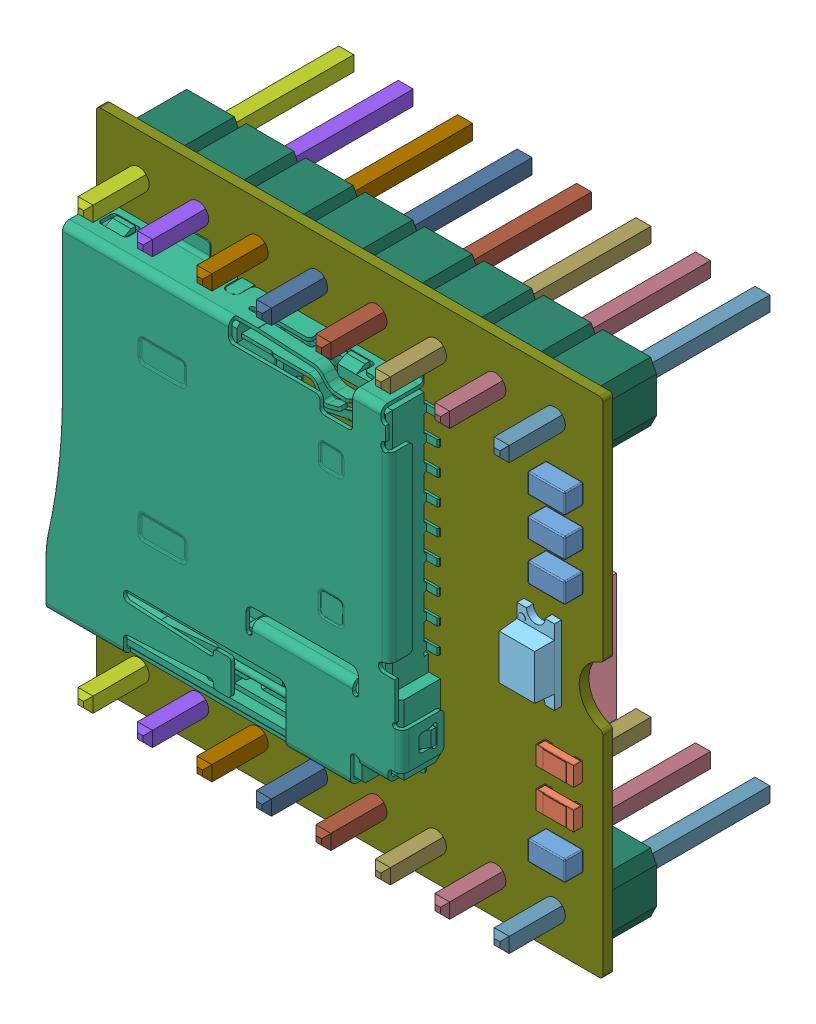
SolidWorks assembly MP3-TF-16P, configuration Default. Lengths in mm.
Overall size (21.94 21.51 11.54).
80 component instances, 16 part files, 0 mates.
Components (placement in the parent):
- Designator45-1: Designator45 [Default] at origin size (1.6 0.86 0.8)
  - User_Library-Chip_Capacitor2CAPC0603X33N-1: User_Library-Chip_Capacitor2CAPC0603X33N [Default] at (15.7476 3.0705 -0.7915) x (-1 0 0) z (0 0 -1) size (1.6 0.86 0.8)
- Designator44-1: Designator44 [Default] at origin size (1.6 0.86 0.8)
  - User_Library-Chip_Capacitor2CAPC0603X33N-1: User_Library-Chip_Capacitor2CAPC0603X33N [Default] at (19.202 3.0705 -0.7915) x (-1 0 0) z (0 0 -1) size (1.6 0.86 0.8)
- Designator43-1: Designator43 [Default] at origin size (1.6 0.86 0.8)
  - User_Library-Chip_Capacitor2CAPC0603X33N-1: User_Library-Chip_Capacitor2CAPC0603X33N [Default] at (9.042 6.7293 -0.7915) x (-1 0 0) z (0 0 -1) size (1.6 0.86 0.8)
- Designator42-1: Designator42 [Default] at origin size (1.6 0.86 0.8)
  - User_Library-Chip_Capacitor2CAPC0603X33N-1: User_Library-Chip_Capacitor2CAPC0603X33N [Default] at (9.042 8.4227 -0.7915) x (-1 0 0) z (0 0 -1) size (1.6 0.86 0.8)
- Designator41-1: Designator41 [Default] at origin size (1.6 0.86 0.8)
  - User_Library-Chip_Capacitor2CAPC0603X33N-1: User_Library-Chip_Capacitor2CAPC0603X33N [Default] at (9.042 13.5027 -0.7915) x (-1 0 0) z (0 0 -1) size (1.6 0.86 0.8)
- Designator40-1: Designator40 [Default] at origin size (1.6 0.86 0.8)
  - User_Library-Chip_Capacitor2CAPC0603X33N-1: User_Library-Chip_Capacitor2CAPC0603X33N [Default] at (3.073 16.974 -0.7915) x (-1 0 0) z (0 0 -1) size (1.6 0.86 0.8)
- Designator39-1: Designator39 [Default] at origin size (1.6 0.86 0.8)
  - User_Library-Chip_Capacitor2CAPC0603X33N-1: User_Library-Chip_Capacitor2CAPC0603X33N [Default] at (9.4738 16.974 -0.7915) x (-1 0 0) z (0 0 -1) size (1.6 0.86 0.8)
- Designator38-1: Designator38 [Default] at origin size (1.6 0.86 0.8)
  - User_Library-Chip_Capacitor2CAPC0603X33N-1: User_Library-Chip_Capacitor2CAPC0603X33N [Default] at (12.6742 16.974 -0.7915) x (-1 0 0) z (0 0 -1) size (1.6 0.86 0.8)
- Designator37-1: Designator37 [Default] at origin size (1.6 0.86 0.8)
  - User_Library-Chip_Capacitor2CAPC0603X33N-1: User_Library-Chip_Capacitor2CAPC0603X33N [Default] at (19.075 16.974 -0.7915) x (-1 0 0) z (0 0 -1) size (1.6 0.86 0.8)
- Designator27-1: Designator27 [Default] at origin size (1.6 0.8 0.4)
  - User_Library-res0603-1-1: User_Library-res0603-1 [Default] at (12.2682 3.4955 -0.4115) x (1 0 0) z (0 0 -1) size (1.6 0.8 0.4)
- Designator26-1: Designator26 [Default] at origin size (1.6 0.8 0.4)
  - User_Library-res0603-1-1: User_Library-res0603-1 [Default] at (8.8138 3.4955 -0.4115) x (1 0 0) z (0 0 -1) size (1.6 0.8 0.4)
- Designator25-1: Designator25 [Default] at origin size (1.6 0.8 0.4)
  - User_Library-res0603-1-1: User_Library-res0603-1 [Default] at (5.3594 3.4955 -0.4115) x (1 0 0) z (0 0 -1) size (1.6 0.8 0.4)
- Designator24-1: Designator24 [Default] at origin size (1.6 0.8 0.4)
  - User_Library-res0603-1-1: User_Library-res0603-1 [Default] at (1.905 3.4955 -0.4115) x (1 0 0) z (0 0 -1) size (1.6 0.8 0.4)
- Designator23-1: Designator23 [Default] at origin size (1.6 0.8 0.4)
  - User_Library-res0603-1-1: User_Library-res0603-1 [Default] at (9.017 5.461 -0.4115) x (1 0 0) z (0 0 -1) size (1.6 0.8 0.4)
- Designator22-1: Designator22 [Default] at origin size (1.6 0.8 0.4)
  - User_Library-res0603-1-1: User_Library-res0603-1 [Default] at (9.017 10.541 -0.4115) x (1 0 0) z (0 0 -1) size (1.6 0.8 0.4)
- Designator21-1: Designator21 [Default] at origin size (1.6 0.8 0.4)
  - User_Library-res0603-1-1: User_Library-res0603-1 [Default] at (9.017 12.2343 -0.4115) x (1 0 0) z (0 0 -1) size (1.6 0.8 0.4)
- Designator20-1: Designator20 [Default] at origin size (1.6 0.8 0.4)
  - User_Library-res0603-1-1: User_Library-res0603-1 [Default] at (9.017 15.621 -0.4115) x (1 0 0) z (0 0 -1) size (1.6 0.8 0.4)
- Designator19-1: Designator19 [Default] at origin size (1.6 0.8 0.4)
  - User_Library-res0603-1-1: User_Library-res0603-1 [Default] at (6.2484 17.399 -0.4115) x (1 0 0) z (0 0 -1) size (1.6 0.8 0.4)
- Designator18-1: Designator18 [Default] at origin size (1.6 0.8 0.4)
  - User_Library-res0603-1-1: User_Library-res0603-1 [Default] at (15.8496 17.399 -0.4115) x (1 0 0) z (0 0 -1) size (1.6 0.8 0.4)
- Designator17-1: Designator17 [Default] at origin size (5 4 1.75)
  - 1464623456-1: 1464623456 [Default] at (3.556 10.541 -2.1615) size (5 4 1.75)
    - Extruded-1: Extruded [Default] at origin size (5 4 1.75)
- Designator15-1: Designator15 [Default] at origin size (8.5 5.4 1.78)
  - 839474920-1: 839474920 [Default] at (15.621 10.287 -2.1915) size (8.5 5.4 1.78)
    - Extruded_2-1: Extruded_2 [Default] at origin size (8.5 5.4 1.78)
- Designator11-1: Designator11 [Default] at origin size (1.6 0.86 0.8)
  - User_Library-Chip_Capacitor2CAPC0603X33N-1: User_Library-Chip_Capacitor2CAPC0603X33N [Default] at (19.837 4.235 0.38) x (-1 0 0) z (0 0 1) size (1.6 0.86 0.8)
- Designator10-1: Designator10 [Default] at origin size (1.6 0.86 0.8)
  - User_Library-Chip_Capacitor2CAPC0603X33N-1: User_Library-Chip_Capacitor2CAPC0603X33N [Default] at (19.837 14.522 0.38) x (-1 0 0) z (0 0 1) size (1.6 0.86 0.8)
- Designator9-1: Designator9 [Default] at origin size (1.6 0.86 0.8)
  - User_Library-Chip_Capacitor2CAPC0603X33N-1: User_Library-Chip_Capacitor2CAPC0603X33N [Default] at (19.837 16.173 0.38) x (-1 0 0) z (0 0 1) size (1.6 0.86 0.8)
- Designator8-1: Designator8 [Default] at origin size (1.6 0.86 0.8)
  - User_Library-Chip_Capacitor2CAPC0603X33N-1: User_Library-Chip_Capacitor2CAPC0603X33N [Default] at (19.837 17.824 0.38) x (-1 0 0) z (0 0 1) size (1.6 0.86 0.8)
- Designator7-1: Designator7 [Default] at origin size (1.6 3.2 1.1)
  - User_Library-FYLS-1206-1: User_Library-FYLS-1206 [Default] at (18.7229 10.6181 0) x (0 -1 0) z (-1 0 0) size (3.2 1.1 1.6)
- Designator6-1: Designator6 [Default] at origin size (1.6 0.8 0.4)
  - User_Library-res0603-1-1: User_Library-res0603-1 [Default] at (19.812 7.112 0) x (-1 0 0) z (0 0 1) size (1.6 0.8 0.4)
- Designator5-1: Designator5 [Default] at origin size (1.6 0.8 0.4)
  - User_Library-res0603-1-1: User_Library-res0603-1 [Default] at (19.812 5.461 0) x (-1 0 0) z (0 0 1) size (1.6 0.8 0.4)
- Designator4-1: Designator4 [Default] at origin size (15.25 16 2.45)
  - User_Library-MEM2055-00-190-01-A_revG-1: User_Library-MEM2055-00-190-01-A_revG [Default] at (-0.4561 11.7349 0) x (0 -1 0) z (-1 0 0) size (16 2.45 15.25)
- Free-Models-1: Free-Models [Default] at origin size (20.32 20.7 11.54)
  - 65793-1: 65793 [Default] at (10.541 19.558 -1.8) x (1 0 0) z (0 1 0) size (0.64 11.54 0.64)
  - 65793-2: 65793 [Default] at (10.541 1.397 -1.8) x (1 0 0) z (0 1 0) size (0.64 11.54 0.64)
  - 65793_2-1: 65793_2 [Default] at (10.541 19.558 -1.8) x (1 0 0) z (0 1 0) size (0.64 11.54 0.64)
  - 65793_2-2: 65793_2 [Default] at (10.541 1.397 -1.8) x (1 0 0) z (0 1 0) size (0.64 11.54 0.64)
  - 65793_3-1: 65793_3 [Default] at (10.541 1.397 -1.8) x (1 0 0) z (0 1 0) size (0.64 11.54 0.64)
  - 65793_3-2: 65793_3 [Default] at (10.541 19.558 -1.8) x (1 0 0) z (0 1 0) size (0.64 11.54 0.64)
  - 65793_4-1: 65793_4 [Default] at (10.541 19.558 -1.8) x (1 0 0) z (0 1 0) size (0.64 11.54 0.64)
  - 65793_4-2: 65793_4 [Default] at (10.541 1.397 -1.8) x (1 0 0) z (0 1 0) size (0.64 11.54 0.64)
  - 65793_5-1: 65793_5 [Default] at (10.541 19.558 -1.8) x (1 0 0) z (0 1 0) size (0.64 11.54 0.64)
  - 65793_5-2: 65793_5 [Default] at (10.541 1.397 -1.8) x (1 0 0) z (0 1 0) size (0.64 11.54 0.64)
  - 65793_6-1: 65793_6 [Default] at (10.541 19.558 -1.8) x (1 0 0) z (0 1 0) size (0.64 11.54 0.64)
  - 65793_6-2: 65793_6 [Default] at (10.541 1.397 -1.8) x (1 0 0) z (0 1 0) size (0.64 11.54 0.64)
  - 65793_7-1: 65793_7 [Default] at (10.541 19.558 -1.8) x (1 0 0) z (0 1 0) size (0.64 11.54 0.64)
  - 65793_7-2: 65793_7 [Default] at (10.541 1.397 -1.8) x (1 0 0) z (0 1 0) size (0.64 11.54 0.64)
  - 65793_8-1: 65793_8 [Default] at (10.541 19.558 -1.8) x (1 0 0) z (0 1 0) size (0.64 11.54 0.64)
  - 65793_8-2: 65793_8 [Default] at (10.541 1.397 -1.8) x (1 0 0) z (0 1 0) size (0.64 11.54 0.64)
  - 65793_9-1: 65793_9 [Default] at (10.541 19.558 -1.8) x (1 0 0) z (0 1 0) size (20.32 2.54 2.54)
  - 65793_9-2: 65793_9 [Default] at (10.541 1.397 -1.8) x (1 0 0) z (0 1 0) size (20.32 2.54 2.54)
- Board-1: Board [Default] at (0 0 -0.4115) size (21.64 21.51 0.42)
